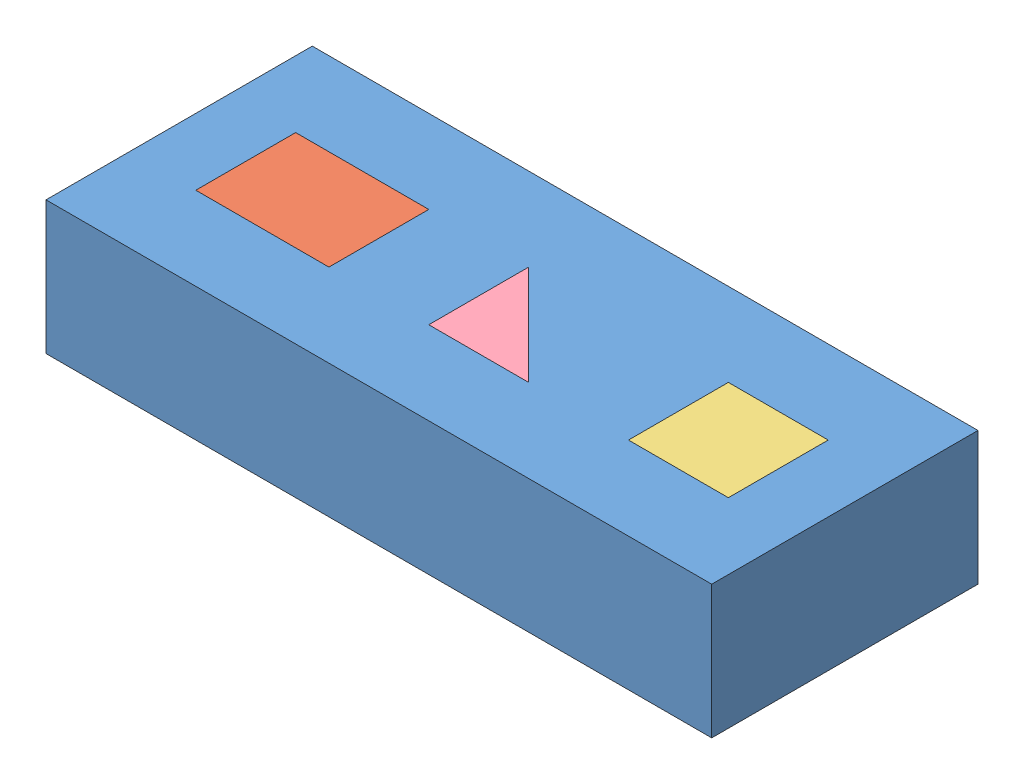
SolidWorks assembly Assem2, configuration Default. Lengths in mm.
Overall size (127 25.4 50.8).
4 component instances, 4 part files, 13 mates.
Components (placement in the parent):
- Block_Coinc_parallel_prepend_2013-1: Block_Coinc_parallel_prepend_2013 [Default] at (-9.9945 50.1012 122.025) size (127 25.4 50.8)
- rectangle_1_2013-1: rectangle_1_2013 [Default] at (2.7055 50.1012 106.15) size (25.4 25.4 19.05)
- Square_2013-1: Square_2013 [Default] at (85.2555 50.1012 87.1) x (0 0 1) z (-1 0 0) size (19.05 25.4 19.05)
- Traingle_2013-1: Traingle_2013 [Default] at (47.1555 50.1012 106.15) size (19.05 25.4 19.05)
Mates (geometry in assembly coordinates):
- Coincident1: coincident aligned: plane of Block_Coinc_parallel_prepend_2013-1 through (-9.9945 75.5012 122.025) normal (0 1 0); plane of rectangle_1_2013-1 through (2.7055 75.5012 106.15) normal (0 1 0)
- Parallel1: parallel aligned: line of Block_Coinc_parallel_prepend_2013-1 through (2.7055 75.5012 106.15) axis (1 0 0); line of rectangle_1_2013-1 through (2.7055 75.5012 106.15) axis (1 0 0)
- Parallel2: parallel aligned: line of Block_Coinc_parallel_prepend_2013-1 through (2.7055 75.5012 106.15) axis (1 0 0); line of rectangle_1_2013-1 through (2.7055 75.5012 106.15) axis (1 0 0)
- Perpendicular1: perpendicular: line of Block_Coinc_parallel_prepend_2013-1 through (2.7055 75.5012 87.1) axis (0 0 1); line of rectangle_1_2013-1 through (2.7055 75.5012 106.15) axis (1 0 0)
- Parallel4: parallel: line of Block_Coinc_parallel_prepend_2013-1 through (2.7055 75.5012 87.1) axis (0 0 1); plane of rectangle_1_2013-1 through (2.7055 75.5012 106.15) normal (0 1 0)
- Coincident6: coincident: point of Block_Coinc_parallel_prepend_2013-1; point of rectangle_1_2013-1
- Parallel5: parallel aligned: plane of Block_Coinc_parallel_prepend_2013-1 through (-9.9945 75.5012 122.025) normal (0 1 0); plane of Traingle_2013-1 through (47.1555 75.5012 106.15) normal (0 1 0)
- Perpendicular2: perpendicular: plane of Block_Coinc_parallel_prepend_2013-1 through (47.1555 50.1012 87.1) normal (1 0 0); plane of Traingle_2013-1 through (47.1555 75.5012 106.15) normal (0 0 1)
- Coincident10: coincident anti-aligned: line of Block_Coinc_parallel_prepend_2013-1 through (47.1555 50.1012 87.1) axis (0 1 0); line of Traingle_2013-1 through (47.1555 75.5012 87.1) axis (0 -1 0)
- Coincident11: coincident aligned: plane of Block_Coinc_parallel_prepend_2013-1 through (-9.9945 75.5012 122.025) normal (0 1 0); plane of Traingle_2013-1 through (47.1555 75.5012 106.15) normal (0 1 0)
- Coincident24: coincident: plane of Block_Coinc_parallel_prepend_2013-1 through (-9.9945 75.5012 122.025) normal (0 1 0); plane of Square_2013-1 through (85.2555 75.5012 87.1) normal (0 1 0)
- Coincident25: coincident: point of Block_Coinc_parallel_prepend_2013-1; point of Square_2013-1
- Coincident26: coincident aligned: line of Block_Coinc_parallel_prepend_2013-1 through (85.2555 75.5012 106.15) axis (1 0 0); line of Square_2013-1 through (85.2555 75.5012 106.15) axis (1 0 0)
